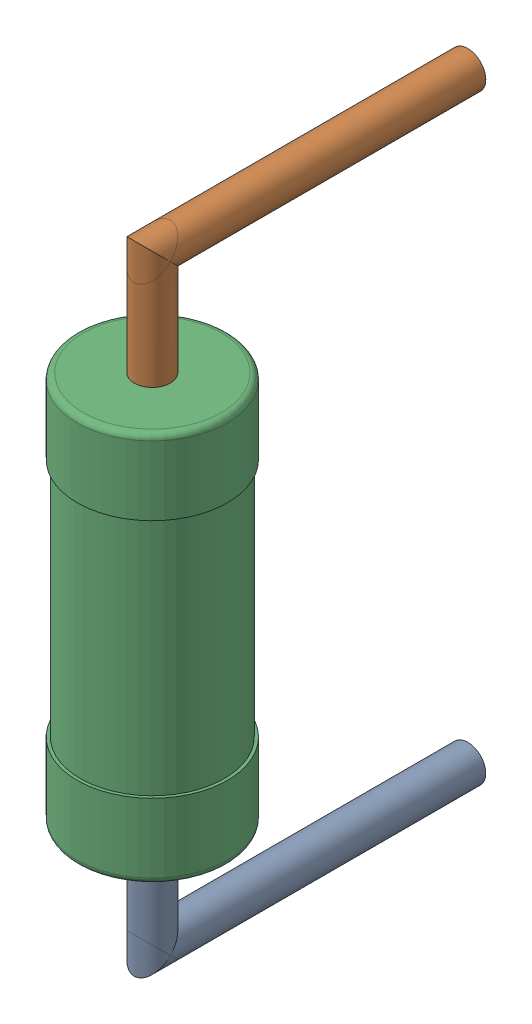
SolidWorks assembly RC.step, configuration Default. Lengths in mm.
Overall size (2.5 10.6 6.5).
3 component instances, 3 part files, 0 mates.
Components (placement in the parent):
- Res_Vishay_BC_Components_MRS25000C1101FCT00_eec.step-1: Res_Vishay_BC_Components_MRS25000C1101FCT00_eec.step [Default] at (35.179 67.31 0) x (0 1 0) z (0 0 1) size (2.05 0.6 5.55)
- Res_Vishay_BC_Components_MRS25000C1101FCT00_eec-2.step-1: Res_Vishay_BC_Components_MRS25000C1101FCT00_eec-2.step [Default] at (35.179 67.31 0) x (0 1 0) z (0 0 1) size (2.05 0.6 5.55)
- Res_Vishay_BC_Components_MRS25000C1101FCT00_eec-3.step-1: Res_Vishay_BC_Components_MRS25000C1101FCT00_eec-3.step [Default] at (35.179 67.31 0) x (0 1 0) z (0 0 1) size (6.5 2.5 2.5)
